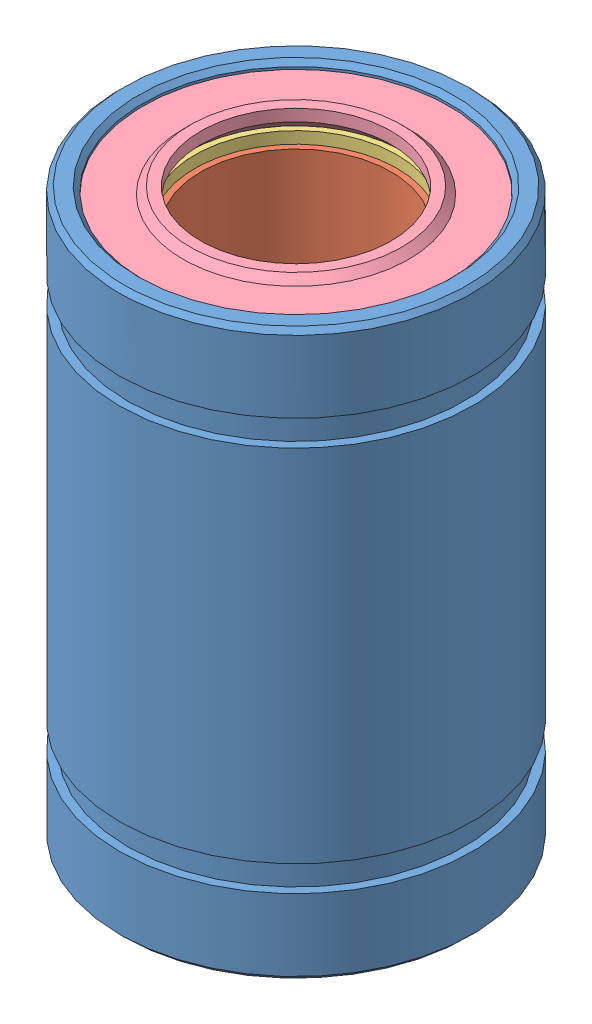
SolidWorks assembly LM8UU, configuration Default. Lengths in mm.
Overall size (19.19 24 19.19).
6 component instances, 4 part files, 10 mates.
Components (placement in the parent):
- Part4-1: Part4 [Default] at origin size (15 24 15)
- Part1-1: Part1 [Default] x (0.874677 0 -0.484707) z (-0.484707 0 -0.874677) size (12.6 21 12.6)
- Part2-1: Part2 [Default] at (0 10.5 0) x (-0.511018 0 -0.85957) z (0.85957 0 -0.511018) size (14 0.5 14)
- Part3-1: Part3 [Default] at (0 -12 0) size (13 1 13)
- Part2-2: Part2 [Default] at (0 -11 0) x (-0.949626 0 -0.313384) z (0.313384 0 -0.949626) size (14 0.5 14)
- Part3-2: Part3 [Default] at (0 12 0) x (0.999124 0 -0.041848) z (-0.041848 0 -0.999124) size (13 1 13)
Mates (geometry in assembly coordinates):
- Concentric1: concentric: cylinder of Part4-1 through (0 12 0) axis (0 1 0) radius 5.9; cylinder of Part1-1 through (0 -10.5 0) axis (0 -1 0) radius 5.8
- Width1: width anti-aligned: plane of Part1-1 through (3.5424 10.5 -1.9631) normal (0 1 0); plane of Part1-1 through (3.5424 -10.5 -1.9631) normal (0 -1 0); plane of Part4-1 through (0 -12 -6.7) normal (0 -1 0); plane of Part4-1 through (0 12 -6.7) normal (0 1 0)
- Concentric3: concentric aligned: cylinder of Part2-1 through (0 11 0) axis (0 -1 0) radius 7; cylinder of Part2-2 through (0 -10.5 0) axis (0 -1 0) radius 7
- Concentric4: concentric anti-aligned: cylinder of Part2-1 through (0 11 0) axis (0 -1 0) radius 7; cylinder of Part3-1 through (0 -9.2365 0) axis (0 1 0) radius 6.5
- Concentric5: concentric anti-aligned: circle of Part2-2; cylinder of Part3-2 through (0 9.2365 0) axis (0 -1 0) radius 6.5
- Concentric6: concentric anti-aligned: cylinder of Part4-1 through (0 12 0) axis (0 1 0) radius 7.5; cylinder of Part3-2 through (0 9.2365 0) axis (0 -1 0) radius 6.5
- Coincident1: coincident anti-aligned: plane of Part4-1 through (0 10.5 -7) normal (0 1 0); plane of Part2-1 through (0 10.5 0) normal (0 -1 0)
- Coincident2: coincident anti-aligned: plane of Part2-1 through (0 11 0) normal (0 1 0); plane of Part3-2 through (4.546 11 -0.1904) normal (0 -1 0)
- Coincident3: coincident anti-aligned: plane of Part4-1 through (0 -10.5 -7) normal (0 -1 0); plane of Part2-2 through (0 -10.5 0) normal (0 1 0)
- Coincident4: coincident anti-aligned: plane of Part3-1 through (4.55 -11 0) normal (0 1 0); plane of Part2-2 through (0 -11 0) normal (0 -1 0)
